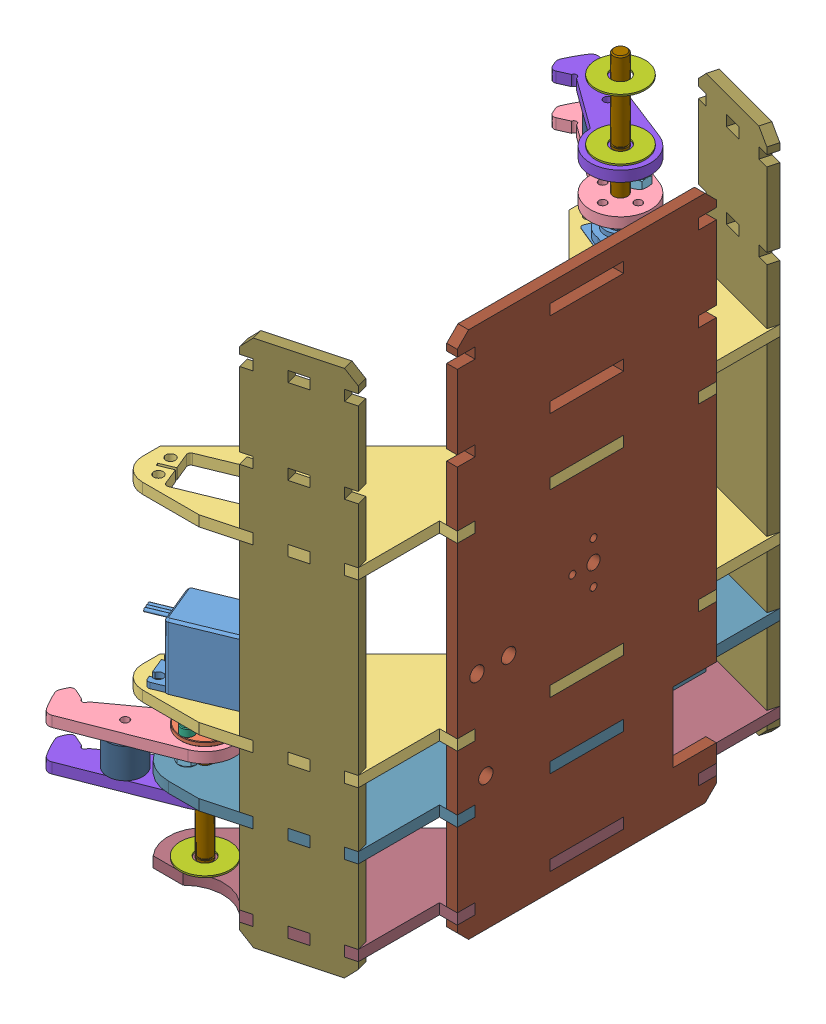
SolidWorks assembly Double Gripper Assm rA.01, configuration Default. Lengths in mm.
Overall size (176.69 237.58 246.95).
43 component instances, 18 part files, 12 mates.
Components (placement in the parent):
- Gripper Assm rA.01-1: Gripper Assm rA.01 [Default] at origin size (176.69 106.01 233.48)
  - 1718 GLYPH BLACK-1: 1718 GLYPH BLACK [Default] at (-76.2 0 0) size (152.4 152.4 152.4) (hidden)
  - 1718 GLYPH BLACK-2: 1718 GLYPH BLACK [Default] at (-152.4 0 0) x (0.707107 0 0.707107) z (-0.707107 0 0.707107) size (152.4 152.4 152.4) (hidden)
  - Grabber Paddle-1: Grabber Paddle [Default] at origin
  - TETRIX_739197_SERVO_2012-1: TETRIX_739197_SERVO_2012 [Default] at (-7.184 35.6 -93.4511) x (-0.380109 0 0.924942) z (-0.924942 0 -0.380109) size (20 43.2 56.76)
  - 8699-17-307 Gripper Mount Structure-1: 8699-17-307 Gripper Mount Structure [Default] at origin
  - Tetrix Servo Hub Metal Light Duty-1: Tetrix Servo Hub Metal Light Duty [Default] at (-7.184 55.1 -93.4511) size (22 6.2 22)
  - 8699-17-314 Gripper Strut ServoMnt-1: 8699-17-314 Gripper Strut ServoMnt [Default] at (63.1261 38.1 0) size (100 4.76 220)
  - 8699-17-315 Gripper Strut Axle-1: 8699-17-315 Gripper Strut Axle [Default] at (63.1261 67.8 0) size (94.86 4.76 220) (hidden)
  - 8699-17-315 Gripper Strut Axle-2: 8699-17-315 Gripper Strut Axle [Default] at (63.1261 105.9 0) size (94.86 4.76 220) (hidden)
  - 8699-17-316 Gripper Right Servoed-1: 8699-17-316 Gripper Right Servoed [Default] at (-7.184 55.1 -93.4511) size (61.04 4.76 43.53)
  - 90631A007 Hex Nut 6-32 Nyloc LoS-1: 90631A007 Hex Nut 6-32 Nyloc LoS [90631A007] at (-7.184 59.8625 -101.4511) size (7.94 4.37 9.17)
  - tetrix_739097 Screw SHC 6-32 0.50Lg-1: tetrix_739097 Screw SHC 6-32 0.50Lg [Default] at (-7.184 53.1 -101.4511) x (-1 0 0) z (0 0 1) size (5.74 16.21 5.74)
  - Washer .31 id-1: Washer .31 id [Default] at (-7.184 72.5625 -93.4511) size (22.17 0.71 22.17)
  - 8699-17-317 Gripper Right Axled-1: 8699-17-317 Gripper Right Axled [Default] at (-7.184 73.2737 -93.4511) size (61.04 4.76 43.53)
  - Washer .31 id-2: Washer .31 id [Default] at (-7.184 105.1888 -93.4511) size (22.17 0.71 22.17)
  - Washer .31 id-3: Washer .31 id [Default] at (-7.184 78.0362 -93.4511) size (22.17 0.71 22.17)
  - 8699-17-318 Shaft - Gripper Grooved-1: 8699-17-318 Shaft - Gripper Grooved [Default] at (-7.184 57.8625 -93.4511) size (6.35 57.15 6.35)
  - 8699-17-319 Grippers Dowel Conn-1: 8699-17-319 Grippers Dowel Conn [Default] at (-28.0465 59.8625 -108.5448) size (15.88 13.41 15.88)
- Gripper Assm rA.01-2: Gripper Assm rA.01 [Default] x (1 0 0) z (0 0 -1) size (176.69 106.01 233.48)
  - 1718 GLYPH BLACK-1: 1718 GLYPH BLACK [Default] at (-76.2 0 0) size (152.4 152.4 152.4) (hidden)
  - 1718 GLYPH BLACK-2: 1718 GLYPH BLACK [Default] at (-152.4 0 0) x (0.707107 0 0.707107) z (-0.707107 0 0.707107) size (152.4 152.4 152.4) (hidden)
  - Grabber Paddle-1: Grabber Paddle [Default] at origin
  - TETRIX_739197_SERVO_2012-1: TETRIX_739197_SERVO_2012 [Default] at (-7.184 35.6 -93.4511) x (-0.380109 0 0.924942) z (-0.924942 0 -0.380109) size (20 43.2 56.76)
  - 8699-17-307 Gripper Mount Structure-1: 8699-17-307 Gripper Mount Structure [Default] at origin
  - Tetrix Servo Hub Metal Light Duty-1: Tetrix Servo Hub Metal Light Duty [Default] at (-7.184 55.1 -93.4511) size (22 6.2 22)
  - 8699-17-314 Gripper Strut ServoMnt-1: 8699-17-314 Gripper Strut ServoMnt [Default] at (63.1261 38.1 0) size (100 4.76 220)
  - 8699-17-315 Gripper Strut Axle-1: 8699-17-315 Gripper Strut Axle [Default] at (63.1261 67.8 0) size (94.86 4.76 220) (hidden)
  - 8699-17-315 Gripper Strut Axle-2: 8699-17-315 Gripper Strut Axle [Default] at (63.1261 105.9 0) size (94.86 4.76 220) (hidden)
  - 8699-17-316 Gripper Right Servoed-1: 8699-17-316 Gripper Right Servoed [Default] at (-7.184 55.1 -93.4511) size (61.04 4.76 43.53)
  - 90631A007 Hex Nut 6-32 Nyloc LoS-1: 90631A007 Hex Nut 6-32 Nyloc LoS [90631A007] at (-7.184 59.8625 -101.4511) size (7.94 4.37 9.17)
  - tetrix_739097 Screw SHC 6-32 0.50Lg-1: tetrix_739097 Screw SHC 6-32 0.50Lg [Default] at (-7.184 53.1 -101.4511) x (-1 0 0) z (0 0 1) size (5.74 16.21 5.74)
  - Washer .31 id-1: Washer .31 id [Default] at (-7.184 72.5625 -93.4511) size (22.17 0.71 22.17)
  - 8699-17-317 Gripper Right Axled-1: 8699-17-317 Gripper Right Axled [Default] at (-7.184 73.2737 -93.4511) size (61.04 4.76 43.53)
  - Washer .31 id-2: Washer .31 id [Default] at (-7.184 105.1888 -93.4511) size (22.17 0.71 22.17)
  - Washer .31 id-3: Washer .31 id [Default] at (-7.184 78.0362 -93.4511) size (22.17 0.71 22.17)
  - 8699-17-318 Shaft - Gripper Grooved-1: 8699-17-318 Shaft - Gripper Grooved [Default] at (-7.184 57.8625 -93.4511) size (6.35 57.15 6.35)
  - 8699-17-319 Grippers Dowel Conn-1: 8699-17-319 Grippers Dowel Conn [Default] at (-28.0465 59.8625 -108.5448) size (15.88 13.41 15.88)
- 8699-17-320 Grippers Back-1: 8699-17-320 Grippers Back [Default] at (71.1261 0 0) size (4.76 237.58 116.59)
- 8699-17-321 Grippers RightSide-1: 8699-17-321 Grippers RightSide [Default] at (21.0131 0 -106.1177) x (0.965926 0 0.258819) z (-0.258819 0 0.965926) size (43.6 237.58 4.76)
- 8699-17-322 Gripper Strut Axle BtmMost-1: 8699-17-322 Gripper Strut Axle BtmMost [Default] at (63.1261 -105.9 0) x (1 0 0) z (0 0 -1) size (94.86 4.76 212.24)
- 8699-17-321 Grippers RightSide-2: 8699-17-321 Grippers RightSide [Default] at (63.1261 0 94.8336) x (-0.965926 0 0.258819) z (-0.258819 0 -0.965926) size (43.6 237.58 4.76)
- 8699-17-323 Gripper Strut Axle 2ndBtmUp-1: 8699-17-323 Gripper Strut Axle 2ndBtmUp [Default] at (63.1261 -67.8 0) x (1 0 0) z (0 0 -1) size (94.86 4.76 220)
Mates (geometry in assembly coordinates):
- Coincident1: coincident aligned: plane of 8699-17-320 Grippers Back-1 through (71.1261 0 0) normal (0 1 0); plane of assembly through (0 0 0) normal (0 1 0)
- Coincident2: coincident aligned: plane of 8699-17-320 Grippers Back-1 through (71.1261 0 0) normal (0 0 1); plane of assembly through (0 0 0) normal (0 0 1)
- Coincident3: coincident aligned: plane of Gripper Assm rA.01-1/8699-17-315 Gripper Strut Axle-2 through (71.1261 110.6625 -58.293) normal (1 0 0); plane of 8699-17-320 Grippers Back-1 through (71.1261 0 0) normal (1 0 0)
- Coincident4: coincident anti-aligned: plane of Gripper Assm rA.01-1/8699-17-314 Gripper Strut ServoMnt-1 through (6.5242 42.8625 -110) normal (0.258819 0 -0.965926); plane of 8699-17-321 Grippers RightSide-1 through (21.0131 0 -106.1177) normal (-0.258819 0 0.965926)
- Coincident5: coincident aligned: plane of 8699-17-321 Grippers RightSide-1; plane of assembly through (0 0 0) normal (0 1 0)
- Coincident6: coincident aligned: plane of Gripper Assm rA.01-1/8699-17-315 Gripper Strut Axle-2 through (71.1261 110.6625 -92.69) normal (1 0 0); plane of 8699-17-321 Grippers RightSide-1
- Coincident7: coordinate: point of Gripper Assm rA.01-2/8699-17-315 Gripper Strut Axle-2; point of 8699-17-322 Gripper Strut Axle BtmMost-1
- Coincident8: coincident: plane of 8699-17-321 Grippers RightSide-1 through (21.0131 0 -106.1177) normal (0.965926 0 0.258819); point of 8699-17-322 Gripper Strut Axle BtmMost-1
- Coincident9: coincident anti-aligned: plane of Gripper Assm rA.01-1/8699-17-314 Gripper Strut ServoMnt-1 through (63.1261 42.8625 94.8336) normal (0.258819 0 0.965926); plane of 8699-17-321 Grippers RightSide-2 through (63.1261 0 94.8336) normal (-0.258819 0 -0.965926)
- Coincident10: coincident aligned: plane of 8699-17-321 Grippers RightSide-1; plane of 8699-17-321 Grippers RightSide-2
- Coincident11: coincident: point of Gripper Assm rA.01-1/8699-17-314 Gripper Strut ServoMnt-1; plane of 8699-17-321 Grippers RightSide-2 through (61.8935 118.7905 90.2333) normal (0.965926 0 -0.258819)
- Coincident12: coordinate: point of Gripper Assm rA.01-2/8699-17-315 Gripper Strut Axle-1; point of 8699-17-323 Gripper Strut Axle 2ndBtmUp-1
